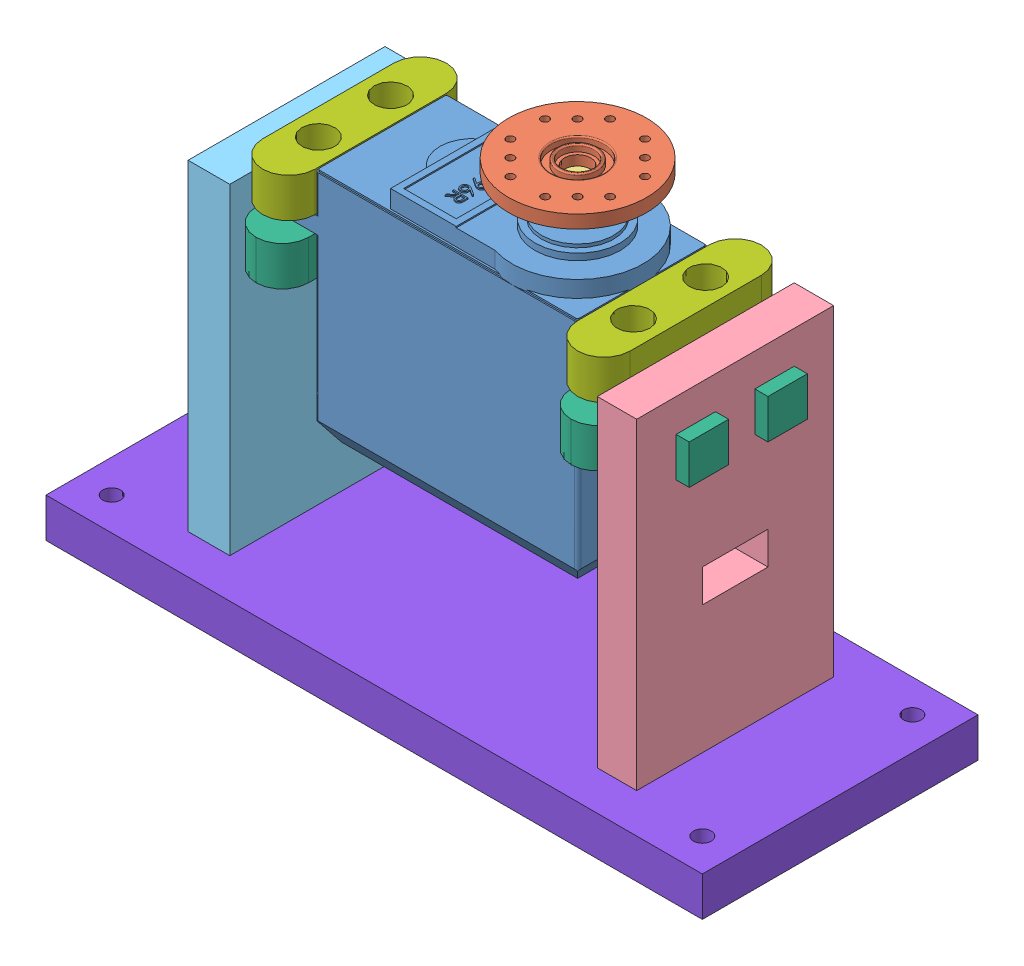
SolidWorks assembly Robot, configuration Default. Lengths in mm.
Overall size (100 70 72.08).
11 component instances, 8 part files, 22 mates.
Components (placement in the parent):
- Servo_Assembly-1: Servo_Assembly [Predeterminado] at (-0.5442 -30.416 73.1756) x (-0.562335 0 0.82691) z (-0.82691 0 -0.562335) size (48.03 47.5 57.55)
  - MG996R Servo-1: MG996R Servo [Predeterminado] at (2.2905 -18.8491 62.2691) x (0.562335 0 0.82691) z (-0.82691 0 0.562335) size (56 40 20)
  - Servo_Disk-1: Servo_Disk [Predeterminado] at (-3.3329 26.6509 54) x (0.186077 0 -0.982535) z (0.982535 0 0.186077) size (21 5 21)
  - Servo_Flanged Bushing-1: Servo_Flanged Bushing [Predeterminado] at (-3.3329 18.1509 54) size (4 8 4)
- L0_CORD SIDE-1: L0_CORD SIDE [Default] at (-19.3231 -44.2652 40.0536) x (-1 0 0) z (0 0 -1) size (6 55 30)
- L0_FLAT SIDE-1: L0_FLAT SIDE [Default] at (-87.6731 -44.2652 40.0536) size (6.35 55 30)
- L0_MOTOR BRACKET-1: L0_MOTOR BRACKET [Default] at (-29.3231 -27.7652 40.0536) x (-1 0 0) z (0 0 -1) size (16 6 30)
- L0_MOTOR BRACKET-2: L0_MOTOR BRACKET [Default] at (-77.3231 -27.7652 40.0536) size (16 6 30)
- L0_CLEVIS PLATE-1: L0_CLEVIS PLATE [Default] at (-77.3231 -19.2652 40.0536) x (0 0 -1) z (1 0 0) size (28 6 8)
- L0_CLEVIS PLATE-2: L0_CLEVIS PLATE [Default] at (-29.3231 -19.2652 40.0536) x (0 0 1) z (-1 0 0) size (28 6 8)
- L0_BASE-1: L0_BASE [Default] at (-53.3231 -71.7652 40.0536) size (100 6 42)
Mates (geometry in assembly coordinates):
- Coincident1: coincident anti-aligned: plane of L0_MOTOR BRACKET-1 through (-25.3231 -21.7652 37.0536) normal (1 0 0); plane of L0_CORD SIDE-1 through (-25.3231 -44.2652 40.0536) normal (-1 0 0)
- Coincident2: coincident aligned: line of L0_CORD SIDE-1 through (-25.3231 -21.7652 49.0536) axis (0 -1 0); line of L0_MOTOR BRACKET-1 through (-25.3231 -21.7652 49.0536) axis (0 -1 0)
- Coincident3: coincident aligned: line of L0_CORD SIDE-1 through (-25.3231 -21.7652 49.0536) axis (0 0 -1); line of L0_MOTOR BRACKET-1 through (-25.3231 -21.7652 43.0536) axis (0 0 -1)
- Concentric1: concentric anti-aligned: circle of Servo_Assembly-1/MG996R Servo-1; circle of L0_MOTOR BRACKET-1
- Concentric2: concentric anti-aligned: circle of Servo_Assembly-1/MG996R Servo-1; circle of L0_MOTOR BRACKET-1
- Coincident6: coincident anti-aligned: plane of Servo_Assembly-1/MG996R Servo-1 through (-33.8231 -21.7652 30.0536) normal (0 -1 0); plane of L0_MOTOR BRACKET-1 through (-29.3231 -21.7652 40.0536) normal (0 1 0)
- Concentric3: concentric aligned: circle of Servo_Assembly-1/MG996R Servo-1; circle of L0_MOTOR BRACKET-2
- Concentric4: concentric aligned: circle of Servo_Assembly-1/MG996R Servo-1; circle of L0_MOTOR BRACKET-2
- Coincident7: coincident anti-aligned: plane of Servo_Assembly-1/MG996R Servo-1 through (-72.8231 -21.7652 30.0536) normal (0 -1 0); plane of L0_MOTOR BRACKET-2 through (-77.3231 -21.7652 40.0536) normal (0 1 0)
- Concentric5: concentric anti-aligned: circle of Servo_Assembly-1/MG996R Servo-1; circle of L0_CLEVIS PLATE-2
- Concentric6: concentric anti-aligned: circle of Servo_Assembly-1/MG996R Servo-1; circle of L0_CLEVIS PLATE-2
- Coincident8: coincident anti-aligned: plane of Servo_Assembly-1/MG996R Servo-1 through (-33.8231 -19.2652 30.0536) normal (0 1 0); plane of L0_CLEVIS PLATE-2 through (-29.3231 -19.2652 30.0536) normal (0 -1 0)
- Concentric7: concentric aligned: circle of Servo_Assembly-1/MG996R Servo-1; circle of L0_CLEVIS PLATE-1
- Concentric8: concentric aligned: circle of Servo_Assembly-1/MG996R Servo-1; circle of L0_CLEVIS PLATE-1
- Coincident9: coincident anti-aligned: plane of Servo_Assembly-1/MG996R Servo-1 through (-72.8231 -19.2652 30.0536) normal (0 1 0); plane of L0_CLEVIS PLATE-1 through (-77.3231 -19.2652 50.0536) normal (0 -1 0)
- Coincident10: coincident anti-aligned: plane of L0_FLAT SIDE-1 through (-81.3231 -44.2652 40.0536) normal (1 0 0); plane of L0_MOTOR BRACKET-2 through (-81.3231 -21.7652 43.0536) normal (-1 0 0)
- Coincident11: coincident aligned: line of L0_FLAT SIDE-1 through (-81.3231 -21.7652 31.0536) axis (0 0 1); line of L0_MOTOR BRACKET-2 through (-81.3231 -21.7652 37.0536) axis (0 0 1)
- Coincident12: coincident aligned: line of L0_FLAT SIDE-1 through (-81.3231 -21.7652 31.0536) axis (0 -1 0); line of L0_MOTOR BRACKET-2 through (-81.3231 -21.7652 31.0536) axis (0 -1 0)
- Coincident13: coincident aligned: plane of L0_CORD SIDE-1 through (-25.3231 -71.7652 40.0536) normal (0 -1 0); plane of L0_BASE-1 through (-53.3231 -71.7652 40.0536) normal (0 -1 0)
- Coincident14: coincident anti-aligned: line of L0_CORD SIDE-1 through (-19.3231 -71.7652 49.0536) axis (0 0 1); line of L0_BASE-1 through (-19.3231 -71.7652 55.0536) axis (0 0 -1)
- Coincident16: coincident anti-aligned: line of L0_CORD SIDE-1 through (-19.3231 -65.7652 43.0536) axis (0 0 1); line of L0_BASE-1 through (-19.3231 -65.7652 43.0536) axis (0 0 -1)
- Coincident18: coincident anti-aligned: line of L0_CORD SIDE-1 through (-25.3231 -65.7652 49.0536) axis (1 0 0); line of L0_BASE-1 through (-19.3231 -65.7652 49.0536) axis (-1 0 0)
